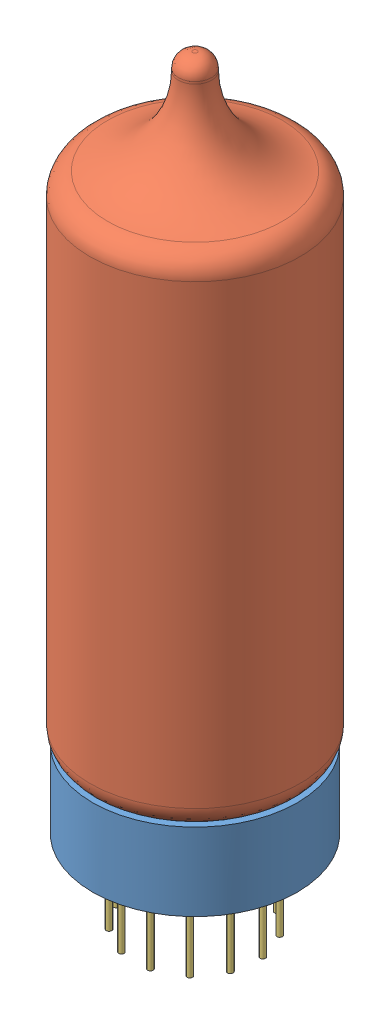
SolidWorks assembly IN-14, configuration Default. Lengths in mm.
Overall size (26.86 68.4 26.86).
4 component instances, 4 part files, 6 mates.
Components (placement in the parent):
- pcb_standoff-1: pcb_standoff [Default] at (7.1038 3.7208 15.749) size (18.5 7 18.5)
- tube_body-1: tube_body [Default] at (7.1038 10.3463 15.749) x (0.727659 0 0.685939) z (-0.685939 0 0.727659) size (19 54.5 19)
- tube_leads-1: tube_leads [Default] at (7.1038 8.4415 15.749) size (11.42 12 11.34)
- flip-1: flip [默认] at (7.0067 32.7424 16.0691) size (18 30 0.1)
Mates (geometry in assembly coordinates):
- Concentric1: concentric aligned: circle of pcb_standoff-1; circle of tube_leads-1
- Concentric2: concentric anti-aligned: circle of pcb_standoff-1; circle of tube_body-1
- Concentric3: concentric aligned: circle of pcb_standoff-1; circle of tube_leads-1
- 平行2: parallel: plane of tube_body-1 through (7.1038 10.3463 15.749) normal (0 -1 0); line of flip-1 through (-1.9933 17.7424 16.0691) axis (1 0 0)
- 锁定1: lock: unknown of tube_body-1; unknown of flip-1
- 锁定2: lock: unknown of tube_body-1; unknown of flip-1
